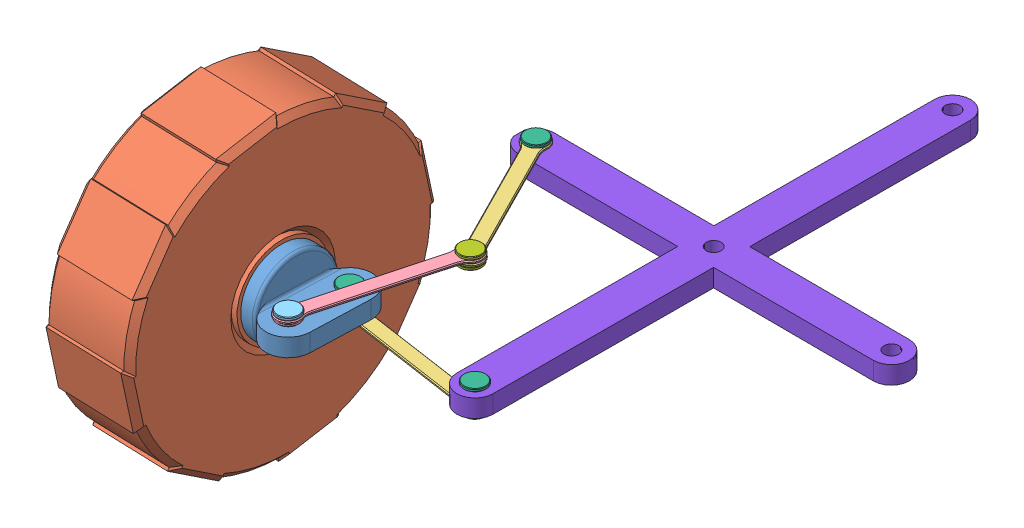
SolidWorks assembly wheel ass, configuration Default. Lengths in mm.
Overall size (16.95 13.84 23.77).
12 component instances, 9 part files, 21 mates.
Components (placement in the parent):
- wheel joint-1: wheel joint [Default] at (1.9879 3.162 2.8726) x (0.999462 0 0.032804) z (-0.032804 0 0.999462) size (6 2.75 3.5)
- wheel-1: wheel [Default] at (1.9879 3.162 2.8726) x (0.999462 0 0.032804) z (0.017949 0.837034 -0.546856) size (3 10 10)
- wheel arm new-1: wheel arm new [Default] at (8.7362 2.862 2.5885) x (0.989182 0 0.146692) z (0 -1 0) size (5.8 0.8 0.1)
- Part1^wheel ass-1: Part1^wheel ass [Default] at origin (virtual)
- wheel arm new 2-1: wheel arm new 2 [Default] at (7.0604 3.662 1.6269) x (0.260162 0 -0.965565) z (0 -1 0) size (5.8 0.8 0.2)
- wheel nutbolt-2: wheel nutbolt [Default] at (6.2028 2.862 4.0115) size (0.74 1 0.74)
- wheel nutbolt0.7-1: wheel nutbolt0.7 [Default] at (6.2684 2.762 2.0126) size (0.74 0.9 0.74)
- wheel arm new-2: wheel arm new [Default] at (6.5485 3.562 -3.1636) x (-0.451524 0 -0.892259) z (0 -1 0) size (5.8 0.8 0.1)
- wheel nutbolt2-1: wheel nutbolt2 [Default] at (7.5036 3.462 -0.8163) x (-0.292743 0 -0.956191) z (0.956191 0 -0.292743) size (0.74 0.4 0.74)
- chasis-1: chasis [Default] at (9.3863 2.862 -2.4431) x (0.999992 0 0.003953) z (-0.003953 0 0.999992) size (13.18 0.6 17.21)
- wheel nutbolt0.7-2: wheel nutbolt0.7 [Default] at (11.2143 2.762 2.746) size (0.74 0.9 0.74)
- wheel nutbolt0.7-3: wheel nutbolt0.7 [Default] at (5.246 2.862 -5.2776) size (0.74 0.9 0.74)
Mates (geometry in assembly coordinates):
- Concentric1: concentric: cylinder of wheel joint-1 through (4.9863 3.162 2.971) axis (-0.999462 0 -0.032804) radius 0.75; cylinder of wheel-1 through (1.9879 3.162 2.8726) axis (0.999462 0 0.032804) radius 0.75
- Coincident1: coincident: plane of wheel joint-1 through (1.9879 3.162 2.8726) normal (0.999462 0 0.032804); plane of wheel-1 through (1.9879 3.162 2.8726) normal (-0.999462 0 -0.032804)
- Concentric2: concentric: cylinder of wheel joint-1 through (6.2684 2.862 2.0126) axis (0 1 0) radius 0.25; cylinder of wheel arm new-1 through (6.2684 2.762 2.0126) axis (0 1 0) radius 0.25
- Coincident2: coincident: plane of wheel arm new-1 through (8.7362 2.862 2.5885) normal (0 1 0); plane of wheel joint-1 through (6.9524 2.862 4.0361) normal (0 -1 0)
- Coincident4: coincident: plane of wheel joint-1 through (6.9524 3.462 4.0361) normal (0 1 0); plane of wheel arm new 2-1 through (6.2028 3.462 4.0115) normal (0 -1 0)
- Concentric5: concentric: cylinder of wheel joint-1 through (6.2028 2.862 4.0115) axis (0 1 0) radius 0.25; cylinder of wheel arm new 2-1 through (6.2028 3.562 4.0115) axis (0 1 0) radius 0.25
- Coincident5: coincident: plane of wheel joint-1 through (6.9524 2.862 4.0361) normal (0 -1 0); plane of wheel nutbolt-2 through (6.2028 2.862 4.0115) normal (0 1 0)
- Concentric6: concentric: cylinder of wheel joint-1 through (6.2028 2.862 4.0115) axis (0 1 0) radius 0.25; cylinder of wheel nutbolt-2 through (6.2028 3.662 4.0115) axis (0 -1 0) radius 0.25
- Coincident6: coincident: plane of wheel joint-1 through (6.9524 3.462 4.0361) normal (0 1 0); plane of wheel nutbolt0.7-1 through (6.2684 3.462 2.0126) normal (0 -1 0)
- Concentric8: concentric: cylinder of wheel joint-1 through (6.2684 2.862 2.0126) axis (0 1 0) radius 0.25; cylinder of wheel nutbolt0.7-1 through (6.2684 3.462 2.0126) axis (0 -1 0) radius 0.25
- Coincident7: coincident: plane of wheel arm new 2-1 through (7.0604 3.562 1.6269) normal (0 -1 0); plane of wheel arm new-2 through (6.5485 3.562 -3.1636) normal (0 1 0)
- Coincident8: coincident: cylinder of wheel arm new 2-1 through (7.5036 3.562 -0.8163) axis (0 1 0) radius 0.25; circle of wheel arm new-2
- Coincident9: coincident: plane of wheel arm new 2-1 through (7.0604 3.662 1.6269) normal (0 1 0); plane of wheel nutbolt2-1 through (7.5036 3.662 -0.8163) normal (0 -1 0)
- Concentric9: concentric: cylinder of wheel arm new 2-1 through (7.5036 3.562 -0.8163) axis (0 1 0) radius 0.25; cylinder of wheel nutbolt2-1 through (7.5036 3.662 -0.8163) axis (0 -1 0) radius 0.25
- Coincident10: coincident: plane of wheel arm new-1 through (8.7362 2.862 2.5885) normal (0 1 0); plane of chasis-1 through (9.3863 2.862 -2.4431) normal (0 -1 0)
- Coincident11: coincident: circle of wheel arm new-1; cylinder of chasis-1 through (11.2143 3.462 2.746) axis (0 -1 0) radius 0.25
- Coincident12: coincident: plane of chasis-1 through (9.3863 3.462 -2.4431) normal (0 1 0); plane of wheel nutbolt0.7-2 through (11.2143 3.462 2.746) normal (0 -1 0)
- Concentric10: concentric: cylinder of chasis-1 through (11.2143 3.462 2.746) axis (0 -1 0) radius 0.25; cylinder of wheel nutbolt0.7-2 through (11.2143 3.462 2.746) axis (0 -1 0) radius 0.25
- Concentric11: concentric: cylinder of wheel arm new-2 through (5.246 3.462 -5.2776) axis (0 1 0) radius 0.25; cylinder of chasis-1 through (5.246 3.462 -5.2776) axis (0 -1 0) radius 0.25
- Coincident13: coincident: plane of chasis-1 through (9.3863 2.862 -2.4431) normal (0 -1 0); plane of wheel nutbolt0.7-3 through (5.246 2.862 -5.2776) normal (0 1 0)
- Concentric12: concentric: cylinder of chasis-1 through (5.246 3.462 -5.2776) axis (0 -1 0) radius 0.25; cylinder of wheel nutbolt0.7-3 through (5.246 3.562 -5.2776) axis (0 -1 0) radius 0.25
